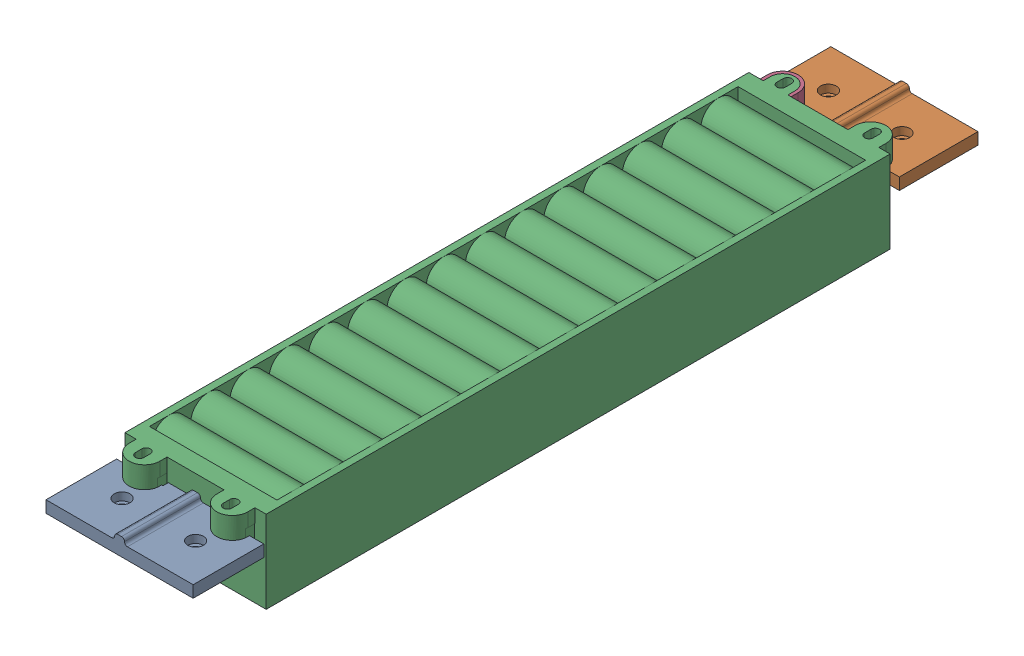
SolidWorks assembly Battery_ASM, configuration Default. Lengths in mm.
Overall size (75 42 400).
3 component instances, 3 part files, 13 mates.
Components (placement in the parent):
- WW0049-2: WW0049 [Default] at origin size (75 12.5 40.5)
- WW0041-3: WW0041 [Default] at (0 0 -355.68) x (-1 0 0) z (0 0 -1) size (75 12.5 45.07)
- Battery_Rev2-3: Battery_Rev2 [Default] at (0 17 -177.715) x (0 0 1) z (1 0 0) size (341 42 72)
Mates (geometry in assembly coordinates):
- Width1: width anti-aligned: plane of WW0041-1 through (159.7516 11.5 40) normal (0 0 1); plane of Battery-1 through (159.7516 11.5 -40) normal (0 0 -1); plane of WW0041-1 through (159 42 -36) normal (0 0 -1); plane of Battery-1 through (159 42 36) normal (0 0 1)
- Parallel1: parallel aligned: plane of Battery-1 through (0 42 0) normal (0 1 0); plane of WW0041-1 through (179.7516 17.5 0) normal (0 1 0)
- Coincident1: coincident anti-aligned: plane of Battery-1 through (162.625 4.5 22.375) normal (0 1 0); circle of WW0041-1
- Coincident2: coincident aligned: plane of WW0049-2 through (-37.5 6 -20.5) normal (-1 0 0); plane of WW0041-3 through (-37.5 6 -334.93) normal (-1 0 0)
- Coincident3: coincident aligned: plane of WW0049-2 through (0 0 0) normal (0 -1 0); plane of WW0041-3 through (0 0 -355.68) normal (0 -1 0)
- Width2: width aligned: plane of WW0049-2 through (37.5 6 -20.5) normal (1 0 0); plane of Battery-2 through (-37.5 6 -20.5) normal (-1 0 0); plane of WW0049-2 through (36 -25 -341) normal (1 0 0); plane of Battery-2 through (-36 -25 -341) normal (-1 0 0)
- Parallel2: parallel aligned: plane of WW0049-2 through (0 0 0) normal (0 -1 0); plane of Battery-2 through (0 -25 -182) normal (0 -1 0)
- Width3: width aligned: plane of WW0041-3 through (37.5 6 -334.93) normal (0 0 1); plane of Battery-2 through (-37.5 6 -20.5) normal (0 0 -1); plane of WW0049-2 through (-36 -25 -23) normal (0 0 1); plane of Battery-2 through (-36 -25 -341) normal (0 0 -1)
- Coincident5: coincident anti-aligned: plane of WW0049-2 through (22.375 12.5 -16.25) normal (0 1 0); plane of Battery-2 through (22.375 12.5 -19.375) normal (0 -1 0)
- Distance2: distance = 400 mm anti-aligned: plane of WW0049-2 through (-37.5 6 20) normal (0 0 1); plane of WW0041-3 through (37.5 6 -380) normal (0 0 -1)
- Width4: width anti-aligned: plane of WW0049-2 through (37.5 6 -20.5) normal (1 0 0); plane of Battery_Rev2-3 through (-37.5 6 -20.5) normal (-1 0 0); plane of WW0049-2 through (-36 17 -177.715) normal (-1 0 0); plane of Battery_Rev2-3 through (36 17 -177.715) normal (1 0 0)
- Width5: width aligned: plane of WW0049-2 through (-37.5 6 -20.5) normal (0 0 -1); plane of Battery_Rev2-3 through (37.5 6 -334.93) normal (0 0 1); plane of WW0041-3 through (36 -25 -336.715) normal (0 0 -1); plane of Battery_Rev2-3 through (36 -25 -18.715) normal (0 0 1)
- Coincident7: coincident anti-aligned: plane of WW0049-2 through (-22.375 12.5 -16.25) normal (0 1 0); plane of Battery_Rev2-3 through (-22.375 12.5 -15.09) normal (0 -1 0)
